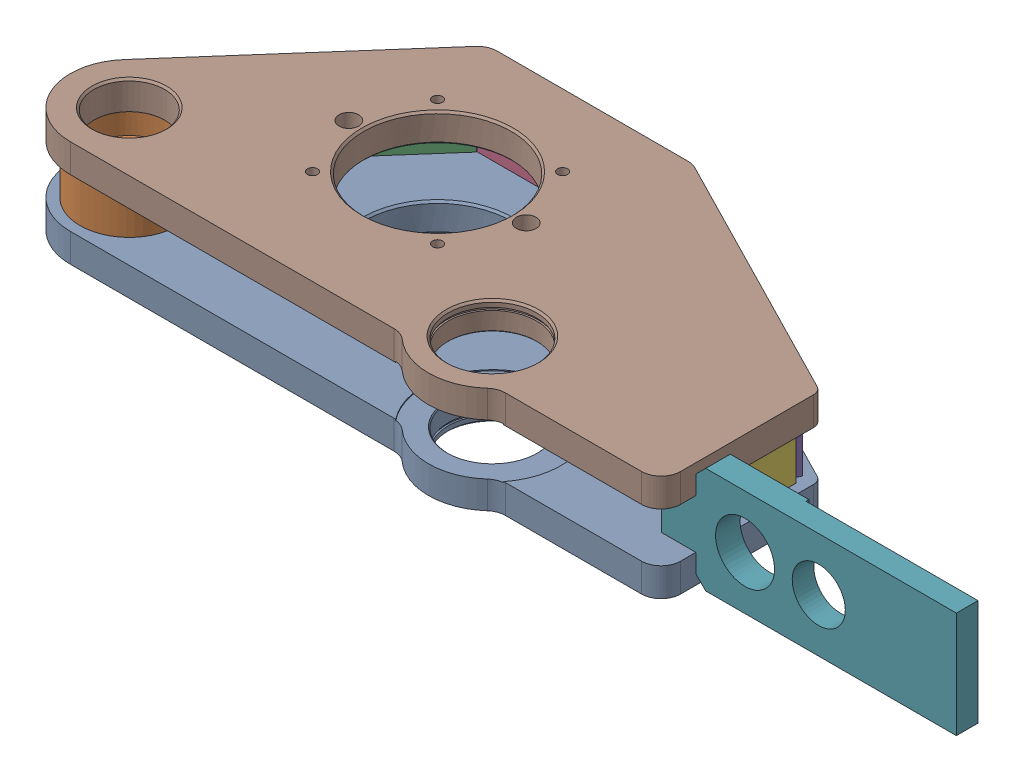
SolidWorks assembly g1_3_1_1_5_1, configuration 默认. Lengths in mm.
Overall size (926 108 318.6).
8 component instances, 8 part files, 0 mates.
Components (placement in the parent):
- g1_3_1_1_5-1_af1_1-1: g1_3_1_1_5-1_af1_1 [默认] at origin size (661 29 318.6)
- g1_3_1_1_5-2_af0_1-1: g1_3_1_1_5-2_af0_1 [默认] at (-213.2 29 0) size (100 50 100)
- g1_3_1_1_5-4_1-1: g1_3_1_1_5-4_1 [默认] at (-149.9151 54 -132.7301) x (0 1 0) z (-0.659692 0 0.751536) size (50 10 223)
- g1_3_1_1_5-5_1-1: g1_3_1_1_5-5_1 [默认] at (20.5 54 -217) x (1 0 0) z (0 1 0) size (194 10 50)
- g1_3_1_1_5-6_1-1: g1_3_1_1_5-6_1 [默认] at (248.4498 54 -161.5242) x (0 1 0) z (0.890083 0 0.455798) size (50 10 284)
- g1_3_1_1_5-7_1-1: g1_3_1_1_5-7_1 [默认] at (377.8 54 -43.9) x (0 0 -1) z (0 1 0) size (87 10 50)
- g1_3_1_1_5-9_af0_1-1: g1_3_1_1_5-9_af0_1 [默认] at (502.8 54 24.6) x (1 0 0) z (0 1 0) size (300 25 108)
- g1_3_1_1_5-1_af0_1-1: g1_3_1_1_5-1_af0_1 [默认] at (0 79 0) size (661 29 318.6)
